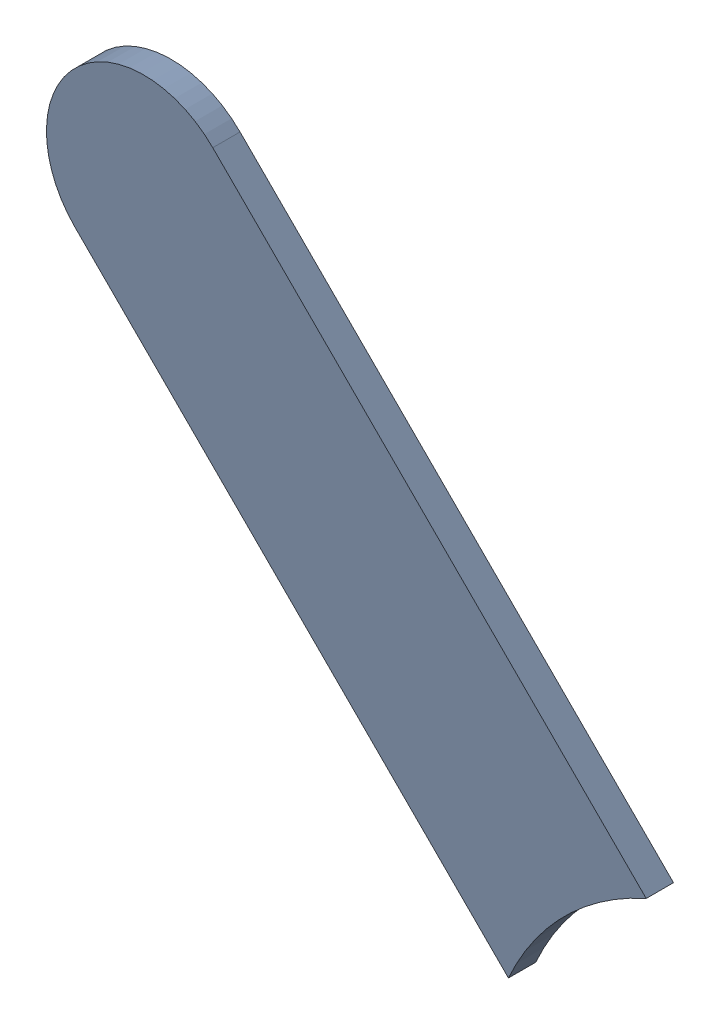
SolidWorks assembly Track (26.95mm,39.35mm)(27.75mm,38.55mm) on Top Layer, configuration Predeterminado. Lengths in mm.
Overall size (0.78 0.78 0.04).
2 component instances, 1 part files, 0 mates.
Components (placement in the parent):
- Track (26.95mm,39.35mm)(27.75mm,38.55mm) on Top Layer-1-1: Track (26.95mm,39.35mm)(27.75mm,38.55mm) on Top Layer-1 [Predeterminado] at (-68.317 -44.187 -0.0457) size (0.78 0.78 0.04)
  - Track (26.95mm,39.35mm)(27.75mm,38.55mm) on Top Layer-Part-1-1: Track (26.95mm,39.35mm)(27.75mm,38.55mm) on Top Layer-Part-1 [Predeterminado] at origin size (0.78 0.78 0.04)
